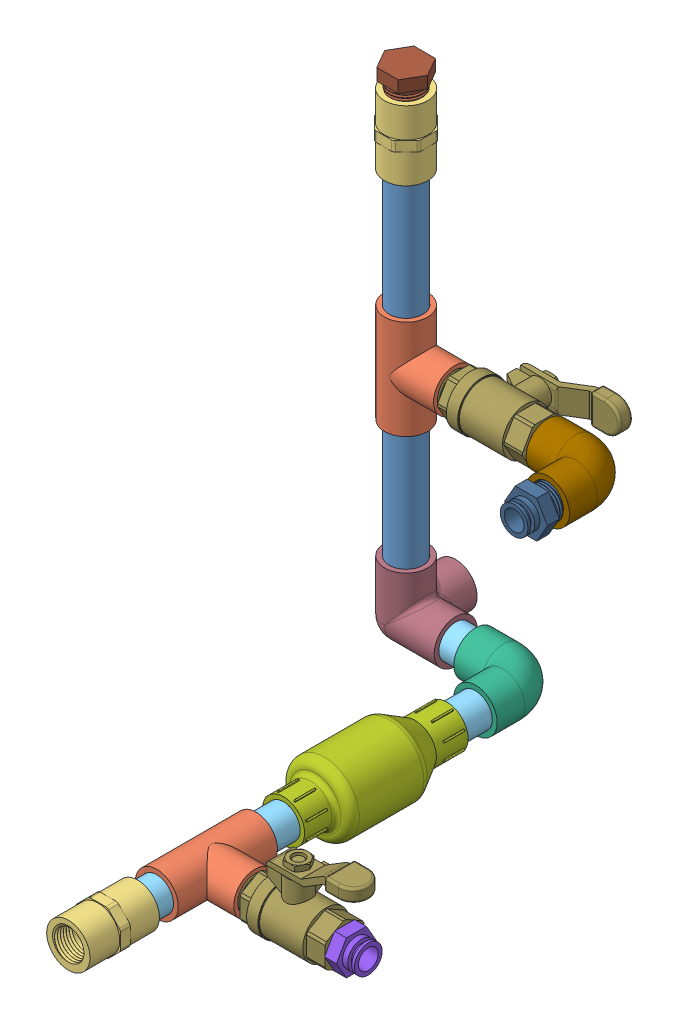
SolidWorks assembly manifold_intake, configuration Default. Lengths in mm.
Overall size (195.82 327.41 334.64).
20 component instances, 13 part files, 70 mates.
Components (placement in the parent):
- pvc-050-0045-1: pvc-050-0045 [Default] at (13.1169 27.275 86.4941) size (21.34 114.3 21.34)
- threaded_tee-1: threaded_tee [4880K392] at (13.1169 153.767 86.4941) x (0 -1 0) z (0 0 1) size (63.5 45.17 27.56)
- pvc-050-0045-2: pvc-050-0045 [Default] at (13.1169 165.959 86.4941) size (21.34 114.3 21.34)
- new adapter-1: new adapter [Default] at (13.1169 305.659 86.4941) x (0.071121 0 -0.997468) z (0 1 0) size (29.21 29.21 45.39)
- TRUE_NIPPLE-1: TRUE_NIPPLE [4830K171] at (102.7698 153.767 86.4941) size (28.84 22.41 22.44)
- pvc-050-0015-1: pvc-050-0015 [Default] at (76.6169 14.575 86.4941) x (0 -0.826891 0.562362) z (0 -0.562362 -0.826891) size (21.34 50.8 21.34)
- unthreaded 90-1: unthreaded 90 [Default] at (89.3169 14.575 118.2441) x (0 1 0) z (0 0 1) size (27.78 45.64 45.64)
- pvc-050-0015-2: pvc-050-0015 [Default] at (89.3169 14.575 149.9941) x (1 0 0) z (0 1 0) size (21.34 50.8 21.34)
- BACKFLOW-1: BACKFLOW [46835K52] at (89.3169 14.575 188.8256) size (44.7 44.7 104.77)
- pvc-050-0015-3: pvc-050-0015 [Default] at (89.3169 14.575 278.4572) x (1 0 0) z (0 1 0) size (21.34 50.8 21.34)
- new adapter-2: new adapter [Default] at (89.3169 14.575 379.0412) x (0.071121 0.997468 0) z (0 0 1) size (29.21 29.21 45.39)
- threaded_tee-2: threaded_tee [4880K392] at (89.3169 14.575 290.6492) x (0 0 -1) z (0 -1 0) size (63.5 45.17 27.56)
- pvc-050-0015-4: pvc-050-0015 [Default] at (89.3169 14.575 302.8412) x (0 1 0) z (1 0 0) size (21.34 50.8 21.34)
- connector_orange-1: connector_orange [Default] at (177.8359 14.575 290.6492) x (0 -0.866025 -0.5) z (0 -0.5 0.866025) size (25.66 23.29 22.23)
- double thread-1: double thread [Default] at (135.6537 153.767 118.2441) x (0 1 0) z (0 0 1) size (27.78 46.58 46.58)
- backflow_inlet-1: backflow_inlet [Default] at (135.6537 153.767 124.5941) x (-0.5 -0.866025 0) z (-0.866025 0.5 0) size (27.5 33.02 23.81)
- cap-1: cap [Default] at (13.1169 312.009 86.4941) size (27.5 25.4 23.81)
- short valve-1: short valve [47865K13] at (72.1465 153.767 86.4941) x (0 1 0) z (-1 0 0) size (31.24 56.77 85.34)
- side-outlet-elbow-2: side-outlet-elbow [4880K631] at (13.1169 14.575 86.4941) x (-1 0 0) z (0 0 -1) size (45.53 45.53 45.53)
- short valve-2: short valve [47865K13] at (148.3465 14.575 290.6492) x (0 0 1) z (-1 0 0) size (31.24 56.77 85.34)
Mates (geometry in assembly coordinates):
- Concentric1: concentric aligned: circle of pvc-050-0045-1; circle of threaded_tee-1
- Parallel1: parallel aligned: plane of threaded_tee-1 through (44.1049 140.3304 86.4941) normal (1 0 0); plane of assembly through (0 0 0) normal (1 0 0)
- Coincident2: coincident anti-aligned: plane of pvc-050-0045-1 through (13.1169 141.575 86.4941) normal (0 1 0); plane of threaded_tee-1 through (13.1169 141.575 86.4941) normal (0 -1 0)
- Concentric2: concentric aligned: circle of threaded_tee-1; circle of pvc-050-0045-2
- Coincident3: coincident anti-aligned: plane of threaded_tee-1 through (13.1169 165.959 86.4941) normal (0 1 0); plane of pvc-050-0045-2 through (13.1169 165.959 86.4941) normal (0 -1 0)
- Concentric3: concentric anti-aligned: circle of pvc-050-0045-2; circle of new adapter-1
- Parallel2: parallel anti-aligned: plane of new adapter-1 through (-1.1706 286.609 92.4122) normal (-1 0 0); plane of assembly through (0 0 0) normal (1 0 0)
- Coincident5: coincident anti-aligned: plane of pvc-050-0045-2 through (13.1169 280.259 86.4941) normal (0 1 0); plane of new adapter-1 through (13.1169 280.259 86.4941) normal (0 -1 0)
- Concentric4: concentric aligned: circle of pvc-050-0045-1; circle of side-outlet-elbow-2
- Parallel3: parallel aligned: plane of threaded_tee-1 through (44.1049 140.3304 86.4941) normal (1 0 0); plane of side-outlet-elbow-2 through (44.8669 14.575 86.4941) normal (1 0 0)
- Coincident7: coincident anti-aligned: plane of pvc-050-0045-1 through (13.1169 27.275 86.4941) normal (0 -1 0); plane of side-outlet-elbow-2 through (5.2175 27.275 86.4941) normal (0 1 0)
- Coincident10: coincident anti-aligned: plane of side-outlet-elbow-2 through (25.8169 6.6756 86.4941) normal (1 0 0); plane of pvc-050-0015-1 through (25.8169 14.575 86.4941) normal (-1 0 0)
- Concentric6: concentric anti-aligned: circle of side-outlet-elbow-2; circle of pvc-050-0015-1
- Coincident12: coincident anti-aligned: plane of pvc-050-0015-1 through (76.6169 14.575 86.4941) normal (1 0 0); plane of unthreaded 90-1 through (76.6169 14.575 86.4941) normal (-1 0 0)
- Concentric8: concentric anti-aligned: circle of pvc-050-0015-1; circle of unthreaded 90-1
- Perpendicular1: perpendicular: plane of side-outlet-elbow-2 through (-0.6626 46.325 86.4941) normal (0 1 0); plane of unthreaded 90-1 through (89.3169 14.575 118.2441) normal (0 0 1)
- Concentric9: concentric anti-aligned: circle of unthreaded 90-1; circle of pvc-050-0015-2
- Coincident14: coincident anti-aligned: plane of unthreaded 90-1 through (89.3169 14.575 99.1941) normal (0 0 1); plane of pvc-050-0015-2 through (89.3169 14.575 99.1941) normal (0 0 -1)
- Coincident15: coincident anti-aligned: plane of pvc-050-0015-2 through (89.3169 14.575 149.9941) normal (0 0 1); plane of BACKFLOW-1 through (89.3169 25.243 149.9941) normal (0 0 -1)
- Coincident17: coincident anti-aligned: plane of pvc-050-0015-2 through (89.3169 14.575 149.9941) normal (0 0 1); plane of BACKFLOW-1 through (89.3169 25.243 149.9941) normal (0 0 -1)
- Concentric10: concentric anti-aligned: circle of pvc-050-0015-2; cylinder of BACKFLOW-1 through (89.3169 14.575 241.2131) axis (0 0 1) radius 10.668
- Concentric11: concentric anti-aligned: circle of BACKFLOW-1; circle of pvc-050-0015-3
- Coincident19: coincident anti-aligned: plane of BACKFLOW-1 through (89.3169 25.243 227.6572) normal (0 0 1); plane of pvc-050-0015-3 through (89.3169 14.575 227.6572) normal (0 0 -1)
- Concentric12: concentric anti-aligned: circle of pvc-050-0015-3; circle of new adapter-2
- Concentric13: concentric anti-aligned: circle of pvc-050-0015-3; circle of threaded_tee-2
- Coincident20: coincident anti-aligned: plane of pvc-050-0015-3 through (89.3169 14.575 278.4572) normal (0 0 1); plane of threaded_tee-2 through (89.3169 14.575 278.4572) normal (0 0 -1)
- Parallel4: parallel aligned: plane of side-outlet-elbow-2 through (44.8669 14.575 86.4941) normal (1 0 0); plane of threaded_tee-2 through (120.3049 14.575 277.2126) normal (1 0 0)
- Concentric14: concentric aligned: circle of threaded_tee-2; circle of pvc-050-0015-4
- Coincident22: coincident anti-aligned: plane of threaded_tee-2 through (89.3169 14.575 302.8412) normal (0 0 1); plane of pvc-050-0015-4 through (89.3169 14.575 302.8412) normal (0 0 -1)
- Coincident23: coincident anti-aligned: plane of new adapter-2 through (89.3169 14.575 353.6412) normal (0 0 -1); plane of pvc-050-0015-4 through (89.3169 14.575 353.6412) normal (0 0 1)
- Concentric15: concentric anti-aligned: circle of threaded_tee-2; cylinder of ? through (107.0195 14.575 290.6492) axis (1 0 0) radius 7.8994
- Coincident24: coincident anti-aligned: plane of threaded_tee-2 through (120.3049 14.575 277.2126) normal (1 0 0); plane of ? through (120.3049 14.575 290.6492) normal (-1 0 0)
- Concentric16: concentric anti-aligned: circle of threaded_tee-1; circle of ?
- Coincident26: coincident anti-aligned: plane of TRUE_NIPPLE-1 through (49.5477 153.767 86.4941) normal (1 0 0); plane of ? through (49.5477 153.767 86.4941) normal (-1 0 0)
- Concentric17: concentric aligned: circle of ?; cylinder of ? through (94.9999 153.767 86.4941) axis (1 0 0) radius 7.8994
- Coincident27: coincident anti-aligned: plane of ? through (108.2852 141.2702 79.2791) normal (1 0 0); plane of ? through (108.2852 153.767 86.4941) normal (-1 0 0)
- Concentric18: concentric aligned: circle of threaded_tee-1; circle of ?
- Concentric19: concentric anti-aligned: circle of ?; circle of ?
- Parallel6: parallel aligned: plane of side-outlet-elbow-2 through (13.1169 14.575 54.7441) normal (0 0 -1); plane of ? through (242.2258 14.575 247.6724) normal (0 0 -1)
- Coincident30: coincident anti-aligned: plane of ?; plane of ? through (122.5727 27.0718 283.4341) normal (-1 0 0)
- Coincident31: coincident: plane of ? through (181.3102 14.575 290.6492) normal (1 0 0); plane of ? through (181.3102 14.575 290.6492) normal (-1 0 0)
- Concentric20: concentric anti-aligned: circle of ?; circle of ?
- Concentric21: concentric aligned: circle of ?; circle of connector_orange-1
- Parallel7: parallel aligned: plane of ? through (219.4886 27.0718 297.8642) normal (0 1 0); plane of connector_orange-1 through (189.4382 25.6875 284.2334) normal (0 1 0)
- Distance2: distance = 0.508 mm anti-aligned: plane of ? through (181.3102 14.575 290.6492) normal (1 0 0); plane of connector_orange-1 through (181.8182 14.575 290.6492) normal (-1 0 0)
- Distance3: distance = 2.54 mm anti-aligned: plane of ? through (108.2852 141.2702 79.2791) normal (1 0 0); plane of double thread-1 through (110.8252 153.767 86.4941) normal (-1 0 0)
- Concentric22: concentric anti-aligned: circle of ?; circle of double thread-1
- Distance4: distance = 6.35 mm anti-aligned: plane of backflow_inlet-1 through (135.6537 153.767 124.5941) normal (0 0 -1); plane of double thread-1 through (135.6537 153.767 118.2441) normal (0 0 1)
- Concentric23: concentric anti-aligned: circle of double thread-1; circle of backflow_inlet-1
- Concentric24: concentric anti-aligned: circle of new adapter-1; circle of cap-1
- Distance5: distance = 6.35 mm anti-aligned: plane of cap-1 through (13.1169 312.009 86.4941) normal (0 -1 0); plane of new adapter-1 through (13.1169 305.659 86.4941) normal (0 1 0)
- Concentric26: concentric aligned: circle of pvc-050-0045-1; circle of side-outlet-elbow-2
- Concentric27: concentric anti-aligned: circle of pvc-050-0015-1; circle of side-outlet-elbow-2
- Parallel8: parallel anti-aligned: plane of new adapter-2 through (89.3169 14.575 379.0412) normal (0 0 1); plane of side-outlet-elbow-2 through (13.1169 14.575 54.7441) normal (0 0 -1)
- Coincident34: coincident anti-aligned: plane of pvc-050-0045-1 through (13.1169 27.275 86.4941) normal (0 -1 0); plane of side-outlet-elbow-2 through (5.2175 27.275 86.4941) normal (0 1 0)
- Coincident35: coincident anti-aligned: plane of pvc-050-0015-1 through (25.8169 14.575 86.4941) normal (-1 0 0); plane of side-outlet-elbow-2 through (25.8169 6.6756 86.4941) normal (1 0 0)
- Concentric29: concentric aligned: circle of threaded_tee-2; circle of short valve-2
- Distance8: distance = 3.175 mm anti-aligned: plane of threaded_tee-2 through (120.3049 14.575 277.2126) normal (1 0 0); plane of short valve-2 through (123.4799 36.2201 278.1524) normal (-1 0 0)
- Coincident42: coincident anti-aligned: plane of connector_orange-1 through (177.8359 14.575 290.6492) normal (-1 0 0); plane of short valve-2 through (177.8359 14.575 290.6492) normal (1 0 0)
- Concentric30: concentric aligned: cylinder of connector_orange-1 through (193.0759 14.575 290.6492) axis (1 0 0) radius 6.35; cylinder of short valve-2 through (148.3465 14.575 290.6492) axis (1 0 0) radius 15.621
- Parallel12: parallel anti-aligned: plane of double thread-1 through (135.6537 153.767 118.2441) normal (0 0 1); plane of side-outlet-elbow-2 through (13.1169 14.575 54.7441) normal (0 0 -1)
- Parallel13: parallel aligned: plane of backflow_inlet-1 through (128.7796 141.8607 132.2141) normal (0 -1 0); plane of short valve-1 through (139.8142 141.2702 79.2791) normal (0 -1 0)
- Coincident46: coincident anti-aligned: plane of TRUE_NIPPLE-1 through (103.9037 153.767 86.4941) normal (1 0 0); plane of double thread-1 through (103.9037 153.767 86.4941) normal (-1 0 0)
- Concentric31: concentric anti-aligned: circle of TRUE_NIPPLE-1; circle of double thread-1
- Concentric32: concentric anti-aligned: circle of threaded_tee-1; circle of short valve-1
- Distance9: distance = 3.175 mm anti-aligned: plane of short valve-1 through (47.2799 141.2702 64.849) normal (-1 0 0); plane of threaded_tee-1 through (44.1049 140.3304 86.4941) normal (1 0 0)
- Coincident48: coincident anti-aligned: plane of TRUE_NIPPLE-1 through (101.6359 153.767 86.4941) normal (-1 0 0); plane of short valve-1 through (101.6359 153.767 86.4941) normal (1 0 0)
- Concentric33: concentric aligned: circle of TRUE_NIPPLE-1; circle of short valve-1
- Parallel15: parallel aligned: plane of new adapter-2 through (83.3988 28.8625 359.9912) normal (0 1 0); plane of short valve-2 through (183.6144 55.723 290.6492) normal (0 1 0)
- Parallel16: parallel aligned: plane of connector_orange-1 through (185.4559 25.6875 284.2334) normal (0 1 0); plane of short valve-2 through (183.6144 55.723 290.6492) normal (0 1 0)
